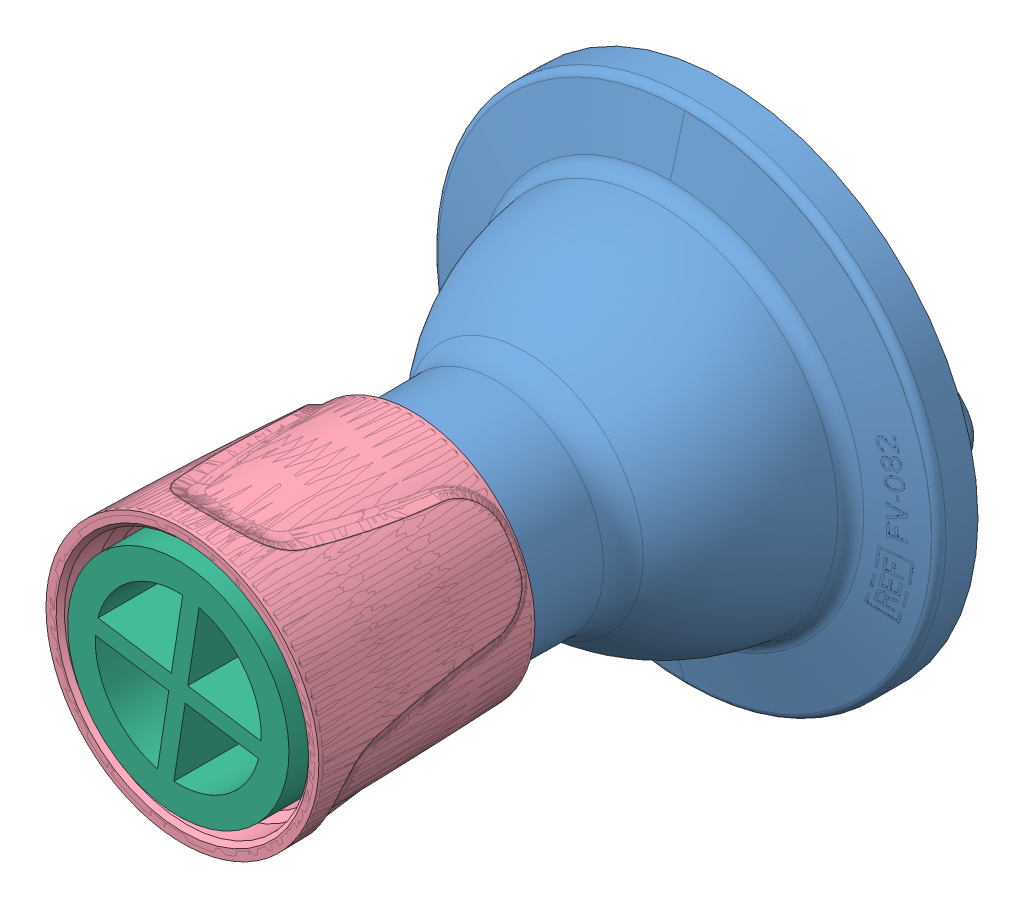
SolidWorks assembly fv_082_asm_LLA, configuration Défaut. Lengths in mm.
Overall size (61 61 74.45).
6 component instances, 6 part files, 0 mates.
Components (placement in the parent):
- AB_464-1: AB_464 [Défaut] at origin size (61 61 48.83)
- FV_074_ORING_9_25X1_78_MONTE-1: FV_074_ORING_9_25X1_78_MONTE [Défaut] at (0 0 13.6) size (13.26 13.26 1.78)
- DB_065_MONTE-1: DB_065_MONTE [Défaut] at (0 0 1.2) x (0 0 1) z (0 1 0) size (13.16 19.87 19.72)
- AB_461-1: AB_461 [Défaut] at (0 0 42.94) x (1 0 0) z (0 1 0) size (32.9 38.75 32.9)
- AB_456_REV_B-2-1: AB_456_REV_B-2 [Défaut] at (0 0 -7.5) x (1 0 0) z (0 1 0) size (11.2 6.76 11.2)
- GOULOT_BOUTEILLE_POUDRE-1: GOULOT_BOUTEILLE_POUDRE [Défaut] at (0 0 43.44) x (-0.988314 0.152433 0) z (-0.152433 -0.988314 0) size (28.36 20 28.33)
